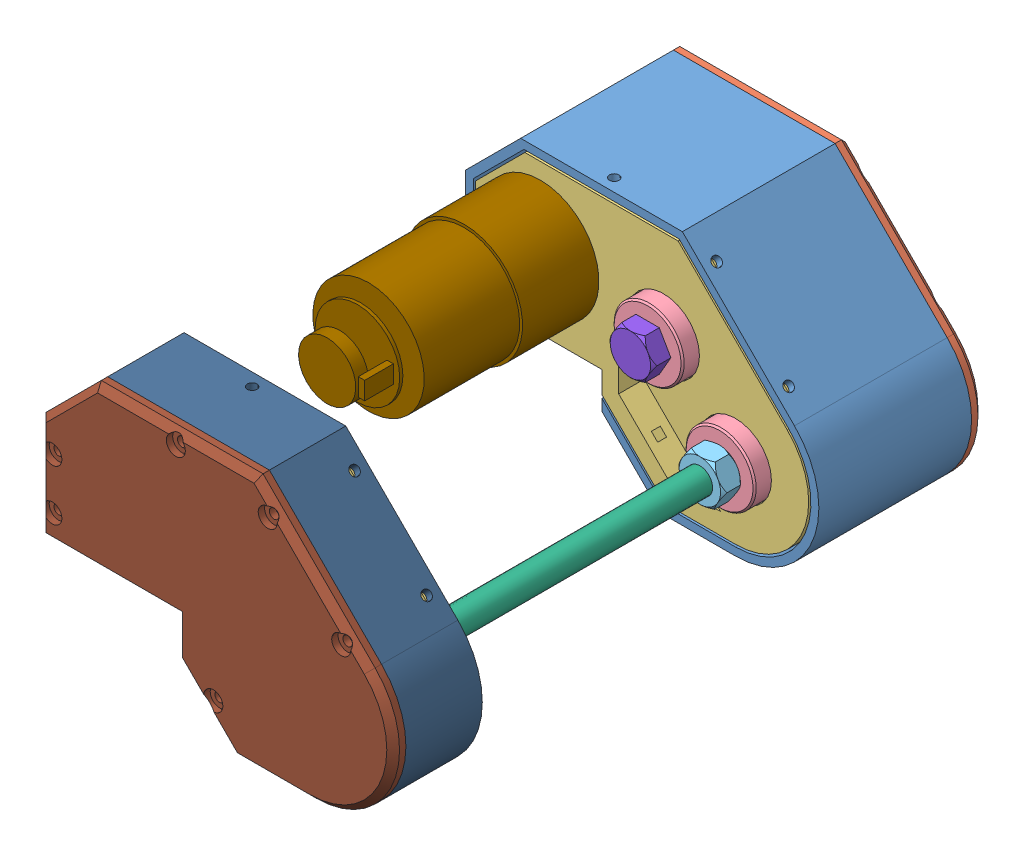
SolidWorks assembly 1_gripper_assembly, configuration Valor predeterminado. Lengths in mm.
Overall size (111.1 79.95 185.77).
19 component instances, 11 part files, 0 mates.
Components (placement in the parent):
- 1_support_assembly-1: 1_support_assembly [Valor predeterminado] at (29.2282 35.3643 55.9846) size (111.1 79.95 185.77)
  - motorPlate_case-1: motorPlate_case [Valor predeterminado] at (-65.1774 -10.6604 87.1) size (111.1 79.95 48)
  - motorPlate_lid-1: motorPlate_lid [Valor predeterminado] at (-65.1774 -10.6604 87.1) size (111.1 79.95 4)
  - motorPlate_v2-1: motorPlate_v2 [Valor predeterminado] at (-65.1774 -10.6604 127.1) size (104.7 73.55 8)
  - bearing-1: bearing [Valor predeterminado] at (16.5226 -14.2604 122.1) size (22 22 7)
  - nut-1: nut [Valor predeterminado] at (16.5226 -14.2604 115.9) size (16.51 13 6.2)
  - threaded_rod-2: threaded_rod [Valor predeterminado] at (16.5226 -14.2604 88.6798) x (0.97929 -0.202463 0) z (0 0 1) size (8 8 176)
  - rod_gear_big_simple-1: rod_gear_big_simple [Valor predeterminado] at (16.5226 -14.2604 105.5724) x (0.996059 0.088691 0) z (0 0 -1) size (40.8 40.8 10)
  - nut-2: nut [Valor predeterminado] at (16.5226 -14.2604 105.5724) size (16.51 13 6.2)
  - nut-4: nut [Valor predeterminado] at (16.5226 -14.2604 140.1) x (0.999879 -0.015551 0) z (0 0 1) size (16.51 13 6.2)
  - nut-5: nut [Valor predeterminado] at (16.5226 -14.2604 93.8724) size (16.51 13 6.2)
  - bearing-2: bearing [Valor predeterminado] at (-6.1048 8.367 133.1) size (22 22 7)
  - bearing-3: bearing [Valor predeterminado] at (-6.1048 8.367 122.1) size (22 22 7)
  - bearing-4: bearing [Valor predeterminado] at (16.5226 -14.2604 133.1) size (22 22 7)
  - bolt-1: bolt [Valor predeterminado] at (-6.1048 8.367 145.5) x (1 0 0) z (0 0 -1) size (16.13 12.7 55.4)
  - motor_pololu-1: motor_pololu [Valor predeterminado] at (-44.7934 12.8206 135.1) x (0 -1 0) z (0 0 1) size (36.8 36.8 89)
  - motorPlate_v2-2: motorPlate_v2 [Valor predeterminado] at (-65.1774 -10.6604 240.8668) size (104.7 73.55 8)
  - motorPlate_board_case-1: motorPlate_board_case [Valor predeterminado] at (-65.1774 -10.6604 192.8668) size (111.1 79.95 24)
  - motorPlate_board_lid-1: motorPlate_board_lid [Valor predeterminado] at (-65.1774 -10.6604 264.8668) size (111.1 79.95 4)
